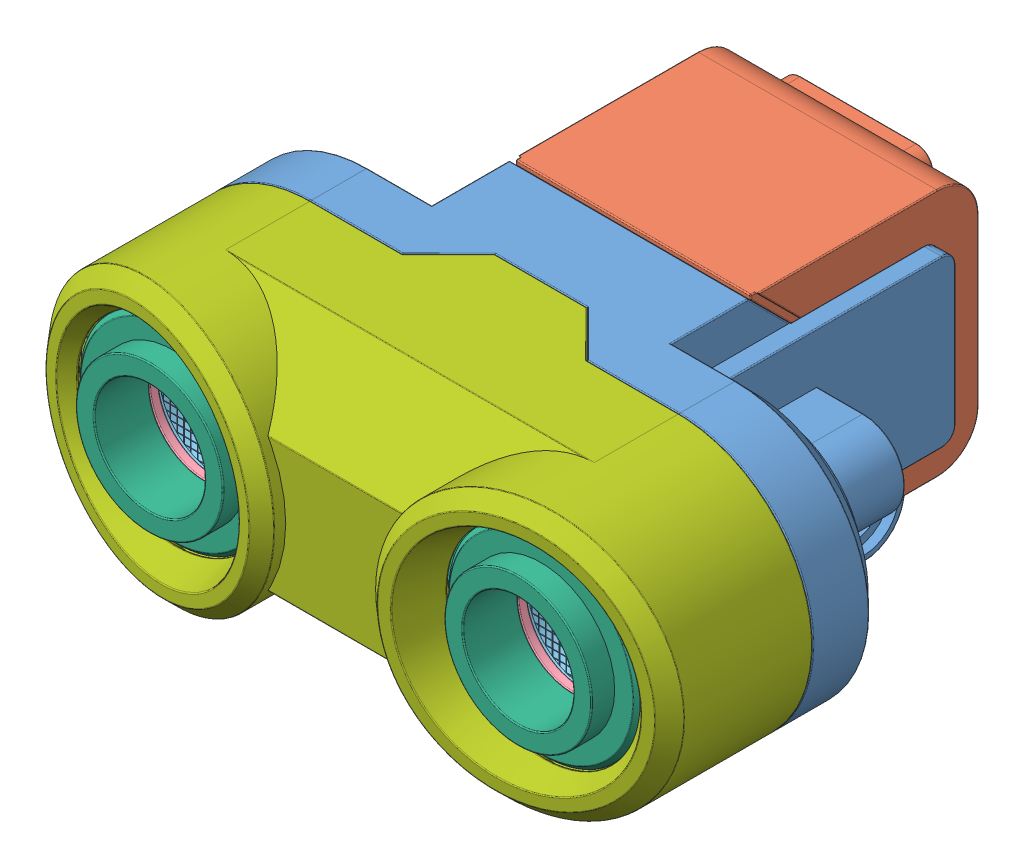
SolidWorks assembly EV3 Ultrasonic Sensor, configuration Default. Lengths in mm.
Overall size (56.01 31.3 47.46).
11 component instances, 8 part files, 0 mates.
Components (placement in the parent):
- 95652.stp-1: 95652.stp [Default] at origin size (56.01 31.3 47.46)
  - 99378-LtBluishGray.stp-1: 99378-LtBluishGray.stp [Default] at origin size (55.2 31.2 31.6)
  - 99376-White.stp-1: 99376-White.stp [Default] at (0 0.8 -19.2) size (22.3 23.6 19.62)
  - 54732b-LtBluishGray.stp-1: 54732b-LtBluishGray.stp [Default] at (0 2.4 -25.2) x (-1 0 0) z (0 0 -1) size (12 14.56 14.4)
  - 99401-RedRubber.stp-1: 99401-RedRubber.stp [Default] at (-16 0 10.8) x (0.443728 0.896161 0) z (0 0 1) size (15.2 15.2 9.6)
  - 99401-RedRubber.stp-2: 99401-RedRubber.stp [Default] at (16 0 10.8) size (15.2 15.2 9.6)
  - 99957-ElectricAlloy.stp-1: 99957-ElectricAlloy.stp [Default] at (-16 0 10.3915) size (12.8 12.8 8.82)
  - 99957-ElectricAlloy.stp-2: 99957-ElectricAlloy.stp [Default] at (16 0 10.3915) size (12.8 12.8 8.82)
  - 10361-TransRed.stp-1: 10361-TransRed.stp [Default] at (0 0 18.4) size (48.8 16.8 14)
  - 99390-Black.stp-1: 99390-Black.stp [Default] at (0 0 6.4) size (56.01 23.5 32.24)
  - 99391-LtBluishGray.stp-1: 99391-LtBluishGray.stp [Default] at (0 0 6) size (49.6 17.6 23.2)
